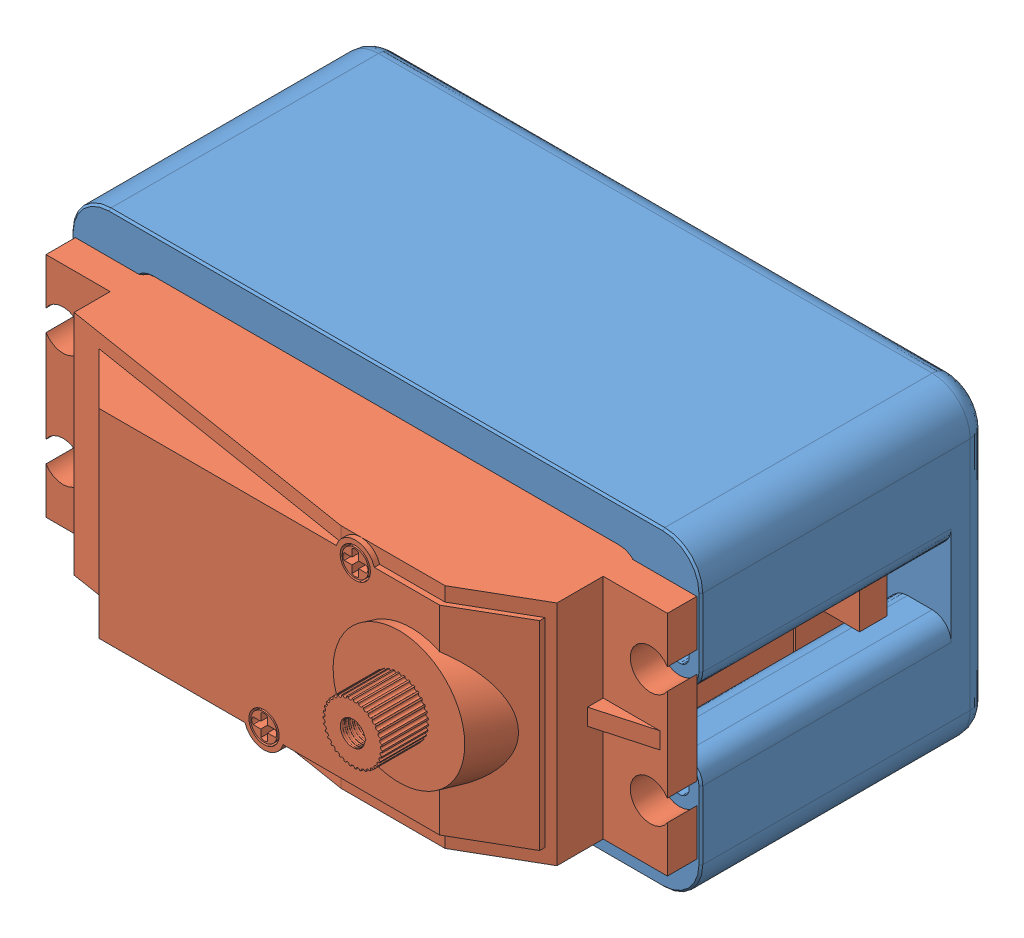
SolidWorks assembly Servo 1_Gimbal System_TVR_UBC Rocket, configuration Default. Lengths in mm.
Overall size (83 41 62.47).
3 component instances, 2 part files, 3 mates.
Components (placement in the parent):
- Assem3^Servo 1_Gimbal System_TVR_UBC Rocket-1: Assem3^Servo 1_Gimbal System_TVR_UBC Rocket [Default] at origin size (83 41 38) (virtual)
  - Servo Casing 1_Gimbla System_TVR_UBC Rocket-1: Servo Casing 1_Gimbla System_TVR_UBC Rocket [Default] at (97.8618 231.9464 179.1196) size (83 41 38)
- 60Kg Servo-1: 60Kg Servo [Default] at (97.8618 231.9464 179.8846) x (-1 0 0) z (0 1 0) size (81.92 55.94 30)
Mates (geometry in assembly coordinates):
- Coincident5: coincident aligned: plane of Assem3^Servo 1_Gimbal System_TVR_UBC Rocket-1/Servo Casing 1_Gimbla System_TVR_UBC Rocket-1 through (97.8618 231.9464 179.1196) normal (0 1 0); plane of 60Kg Servo-1 through (97.8618 231.9464 179.8846) normal (0 1 0)
- Coincident6: coincident anti-aligned: plane of Assem3^Servo 1_Gimbal System_TVR_UBC Rocket-1/Servo Casing 1_Gimbla System_TVR_UBC Rocket-1 through (97.8618 231.9464 179.1196) normal (1 0 0); plane of 60Kg Servo-1 through (97.8618 231.9464 179.8846) normal (-1 0 0)
- Coincident7: coincident anti-aligned: plane of Assem3^Servo 1_Gimbal System_TVR_UBC Rocket-1/Servo Casing 1_Gimbla System_TVR_UBC Rocket-1 through (97.8618 231.9464 195.6196) normal (0 0 1); plane of 60Kg Servo-1 through (138.8218 246.9464 195.6196) normal (0 0 -1)
